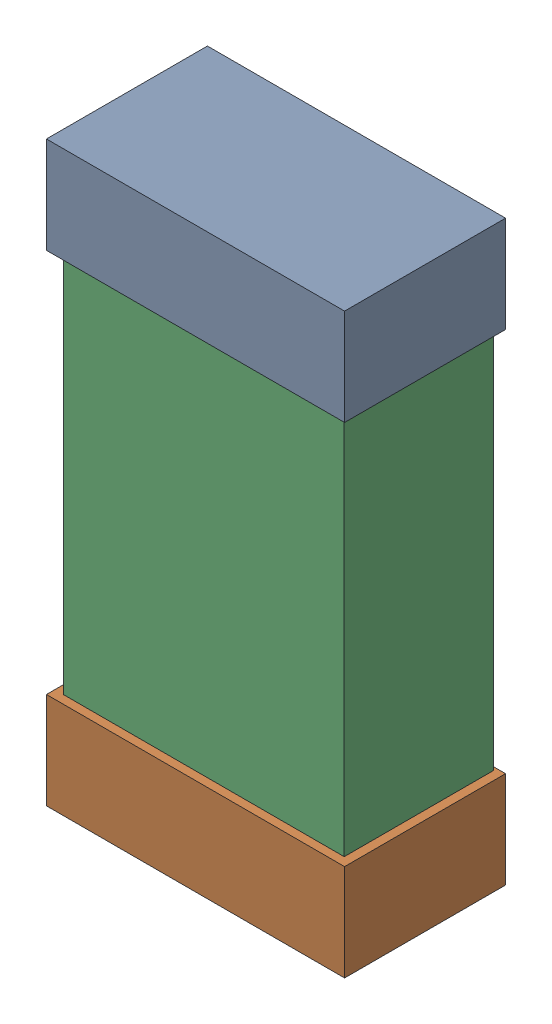
SolidWorks assembly R47, configuration Default. Lengths in mm.
Overall size (0.85 1.65 0.46).
6 component instances, 2 part files, 0 mates.
Components (placement in the parent):
- 432138512_10-1: 432138512_10 [Default] at (39.9168 52.3358 -0.8715) size (0.85 0.28 0.46)
  - Extruded-1: Extruded [Default] at origin size (0.85 0.28 0.46)
- 432138512_11-1: 432138512_11 [Default] at (39.9168 50.9642 -0.8715) size (0.85 0.28 0.46)
  - Extruded-1: Extruded [Default] at origin size (0.85 0.28 0.46)
- 432124816_5-1: 432124816_5 [Default] at (39.9168 51.65 -0.8615) size (0.8 1.5 0.42)
  - Extruded (1)-1: Extruded (1) [Default] at origin size (0.8 1.5 0.42)
